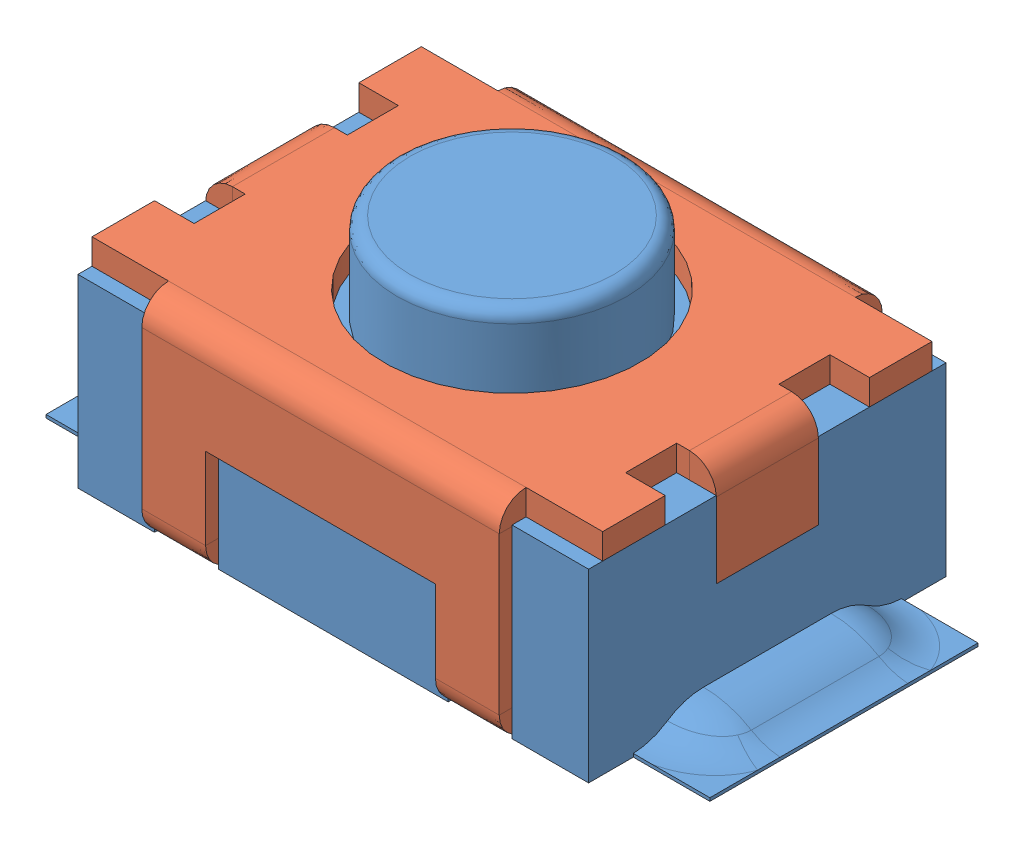
SolidWorks assembly Reset Button, configuration Default. Lengths in mm.
Overall size (5.2 2.15 3).
2 component instances, 2 part files, 3 mates.
Components (placement in the parent):
- Reset Core-1: Reset Core [Default] at origin size (5.2 2.15 2.8)
- Reset Shell-1: Reset Shell [Default] at (0 1.65 0) x (0 0 1) z (-1 0 0) size (3 1.65 4)
Mates (geometry in assembly coordinates):
- Coincident1: coincident anti-aligned: plane of reset core-1 through (0 1.45 0) normal (0 1 0); plane of reset shell-1 through (0 1.45 0) normal (0 -1 0)
- Concentric1: concentric anti-aligned: cylinder of reset core-1 through (0 2.15 0) axis (0 -1 0) radius 0.9; cylinder of reset shell-1 through (0 -8.35 0) axis (0 1 0) radius 1
- Parallel1: parallel aligned: plane of reset core-1 through (-2 1.45 -1.4) normal (-1 0 0); plane of reset shell-1 through (-2 1.65 0) normal (-1 0 0)
